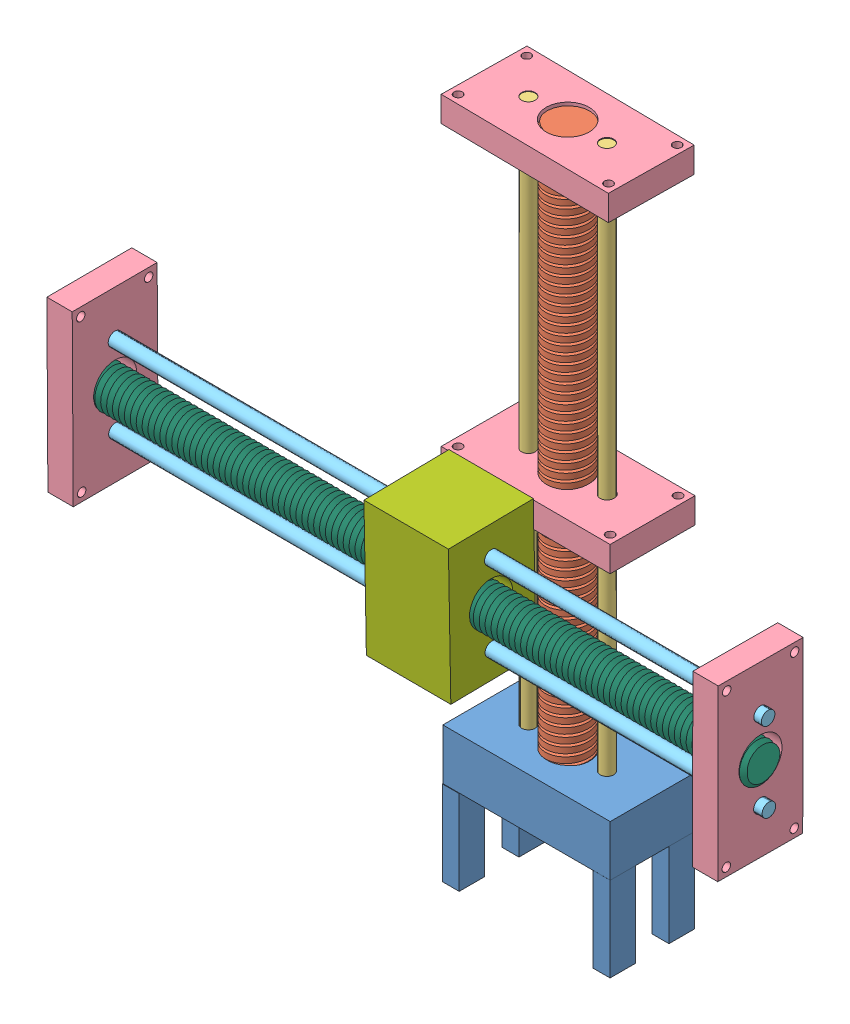
SolidWorks assembly Ensamblaje3, configuration Predeterminado. Lengths in mm.
Overall size (405 401.07 101.45).
14 component instances, 7 part files, 2 mates.
Components (placement in the parent):
- Ensamblaje bueno cx-1: Ensamblaje bueno cx [Predeterminado] at (-25.9077 -144.6959 302.5398) size (100.66 401.07 51.29)
  - base eee-1: base eee [Predeterminado] at (-0.8152 27.3003 94.9143) x (1 0 0) z (0 -1 0) size (98.88 50.29 80)
  - Esparrago 35 cm-1: Esparrago 35 cm [Predeterminado] at (2.9773 346.9252 98.1052) x (0.735608 0 -0.677407) z (0 -1 0) size (26.06 26.33 351.78)
  - 355-1: 355 [Predeterminado] at (-20.6483 348.0158 97.3894) x (0.992373 0 -0.123274) z (0 -1 0) size (8 8 350)
  - 355-2: 355 [Predeterminado] at (26.3378 347.8825 97.9987) x (0.990833 0 -0.13509) z (0 -1 0) size (8 8 350)
  - Pieza1-1: Pieza1 [Predeterminado] at (19.6873 168.6036 73.3275) x (0.999996 0 0.002655) z (0 -1 0) size (100 50 15)
  - Pieza1-2: Pieza1 [Predeterminado] at (19.9423 348.3656 73.7464) x (0.999916 0 0.012986) z (0 -1 0) size (100 50 15)
- Ensamblaje bueno 1.2-1: Ensamblaje bueno 1.2 [Predeterminado] at (-141.4338 -20.1095 454.6824) x (-0.000016 0.999982 0.006067) z (-0.999996 0 -0.002655) size (100.42 51.46 404.86)
  - Pieza1-1: Pieza1 [Predeterminado] at (20.4053 -20.4669 100) size (100 50 15)
  - Pieza2-3: Pieza2 [Predeterminado] at (-19.9491 4.5331 -286.8033) x (0.666646 -0.745374 0) z (0 0 1) size (8 8 400)
  - Esparrago 40 cm-3: Esparrago 40 cm [Predeterminado] at (3.8089 2.3936 -285) x (0 0 1) z (0.999111 -0.042152 0) size (404.86 26.06 26.06)
  - Pieza2-4: Pieza2 [Predeterminado] at (27.0509 4.5331 -286.6261) x (0.873737 -0.486398 0) z (0 0 1) size (8 8 400)
  - Base CNC 1-1: Base CNC 1 [Predeterminado] at (33.2507 -2.0707 -72.7816) x (-0.999932 0.011655 0) z (0 0 -1) size (80.09 50.06 50)
  - Pieza1-2: Pieza1 [Predeterminado] at (20.6186 -20.5227 -282.1417) x (0.999964 0.008525 0) z (0 0 1) size (100 50 15)
Mates (geometry in assembly coordinates):
- Coincidente1: coincident: line of assembly; plane of assembly; line of Ensamblaje bueno cx-1/Pieza1-1 through (26.7923 23.9077 425.9551) axis (-0.999996 0 -0.002655); plane of Ensamblaje bueno 1.2-1/Base CNC 1-1 through (-18.5752 24.6224 425.8473) normal (0.002655 0.017721 -0.999839)
- Paralelo3: parallel: plane of assembly; line of assembly; plane of Ensamblaje bueno cx-1/Pieza1-1 through (-73.2073 8.9077 425.6896) normal (-0.002655 0 0.999996); line of Ensamblaje bueno 1.2-1/Base CNC 1-1 through (-18.5752 24.6224 425.8473) axis (-0.999996 0 -0.002655)
